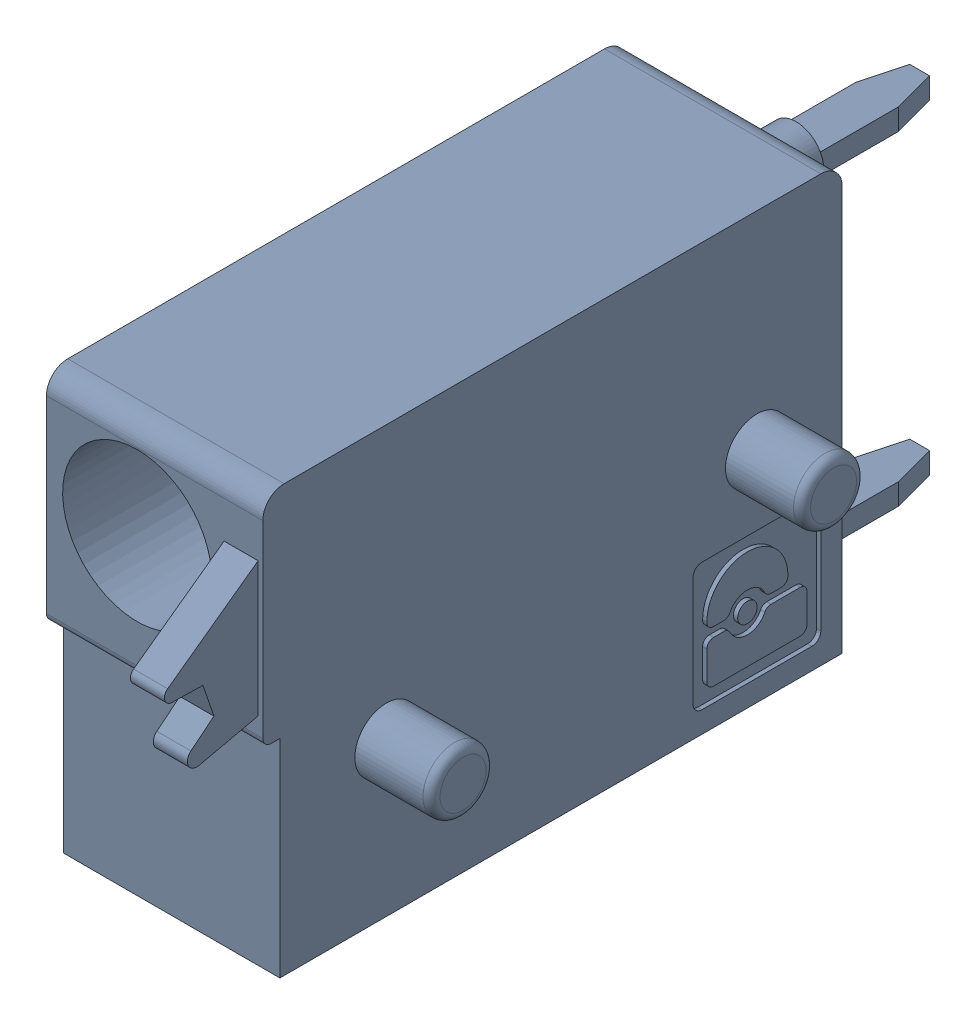
SolidWorks assembly J60, configuration Default. Lengths in mm.
Overall size (6.88 10 19.2).
2 component instances, 1 part files, 0 mates.
Components (placement in the parent):
- 1790348-1: 1790348 [Default] at (177.1651 -7.6199 0) x (0 1 0) z (1 0 0) size (10 19.2 6.88)
  - ffkds-v2-5.08-1: ffkds-v2-5.08 [Default] at (-23.7414 -38.158 -2.54) x (0 -1 0) z (0 0 1) size (19.2 10 6.88)
